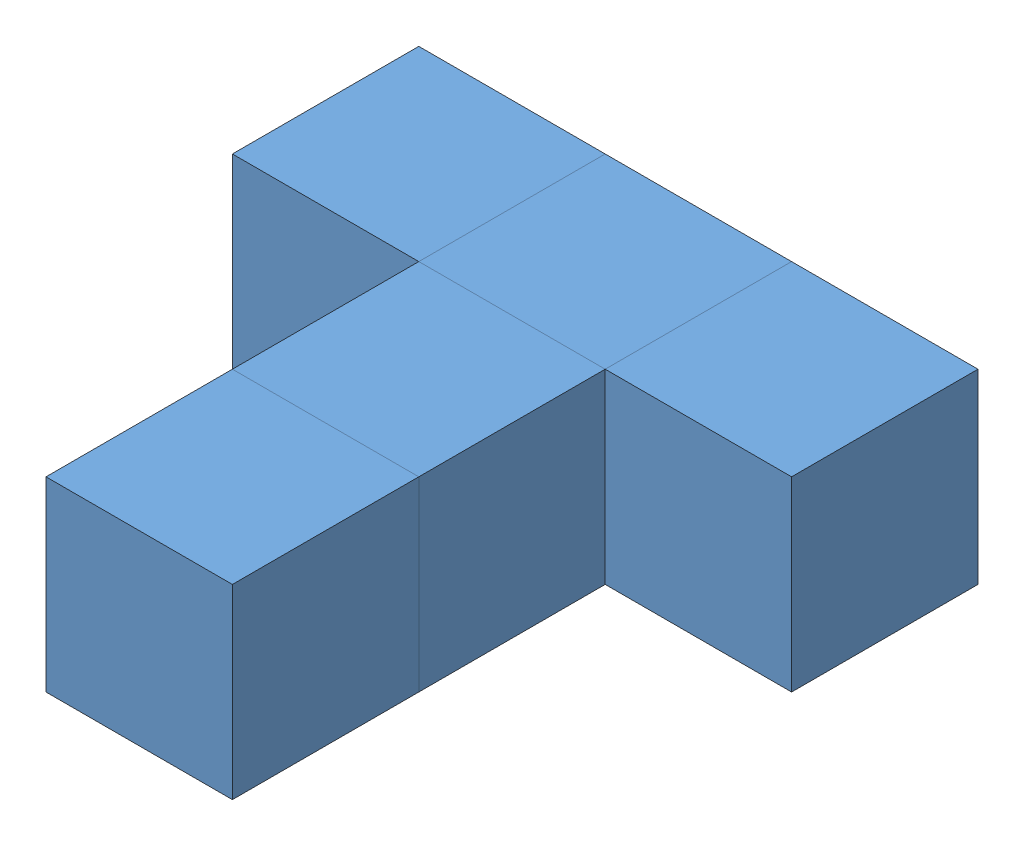
SolidWorks assembly White Piece, configuration Default. Lengths in mm.
Overall size (60 20 60).
5 component instances, 1 part files, 12 mates.
Components (placement in the parent):
- cube-1: cube [Default] at origin size (20 20 20)
- cube-2: cube [Default] at (-20 0 0) size (20 20 20)
- cube-3: cube [Default] at (-40 0 0) size (20 20 20)
- cube-4: cube [Default] at (-20 0 20) size (20 20 20)
- cube-5: cube [Default] at (-20 0 40) size (20 20 20)
Mates (geometry in assembly coordinates):
- Coincident1: coincident aligned: plane of cube-1 through (0 20 0) normal (0 1 0); plane of cube-2 through (-20 20 0) normal (0 1 0)
- Coincident2: coincident aligned: plane of cube-1 through (10 20 10) normal (0 0 1); plane of cube-2 through (-10 20 10) normal (0 0 1)
- Coincident3: coincident anti-aligned: plane of cube-1 through (-10 20 10) normal (-1 0 0); plane of cube-2 through (-10 20 10) normal (1 0 0)
- Coincident4: coincident aligned: plane of cube-2 through (-10 20 10) normal (0 0 1); plane of cube-3 through (-30 20 10) normal (0 0 1)
- Coincident5: coincident anti-aligned: plane of cube-2 through (-30 20 10) normal (-1 0 0); plane of cube-3 through (-30 20 10) normal (1 0 0)
- Coincident6: coincident aligned: plane of cube-2 through (-20 20 0) normal (0 1 0); plane of cube-3 through (-40 20 0) normal (0 1 0)
- Coincident12: coincident anti-aligned: plane of cube-2 through (-10 20 10) normal (0 0 1); plane of cube-4 through (-10 20 10) normal (0 0 -1)
- Coincident13: coincident: line of cube-2 through (-10 20 10) axis (0 0 -1); plane of cube-4 through (-10 20 30) normal (1 0 0)
- Coincident14: coincident aligned: plane of cube-2 through (-20 20 0) normal (0 1 0); plane of cube-4 through (-20 20 20) normal (0 1 0)
- Coincident15: coincident anti-aligned: plane of cube-4 through (-10 20 30) normal (0 0 1); plane of cube-5 through (-10 20 30) normal (0 0 -1)
- Coincident16: coincident aligned: plane of cube-4 through (-20 20 20) normal (0 1 0); plane of cube-5 through (-20 20 40) normal (0 1 0)
- Coincident17: coincident aligned: plane of cube-4 through (-10 20 30) normal (1 0 0); plane of cube-5 through (-10 20 50) normal (1 0 0)
